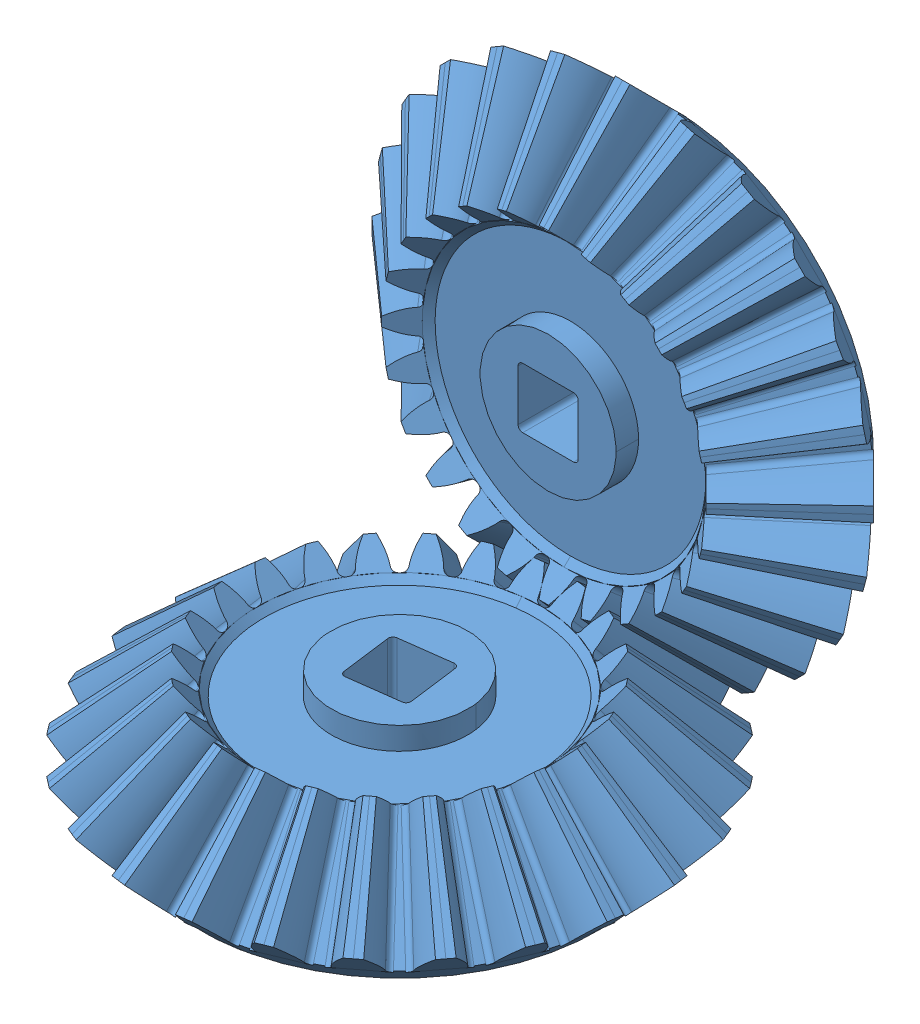
SolidWorks assembly 24T_bevel_gears_meshing, configuration Default. Lengths in mm.
Overall size (30.18 32.23 33.87).
3 component instances, 1 part files, 0 mates.
Components (placement in the parent):
- 24T_Bevel_Gear_276-2184-001.STEP-1: 24T_Bevel_Gear_276-2184-001.STEP [Default] at origin size (30.18 32.23 33.87)
  - Bevel-Gear.STEP-1: Bevel-Gear.STEP [Default] at (0 -12.7043 20.5659) x (0.991445 0 -0.130526) z (0 -1 0) size (26.9 26.9 11.05)
  - Bevel-Gear.STEP-2: Bevel-Gear.STEP [Default] at (0 0 7.8616) x (-1 0 0) z (0 0 -1) size (26.9 26.9 11.05)
